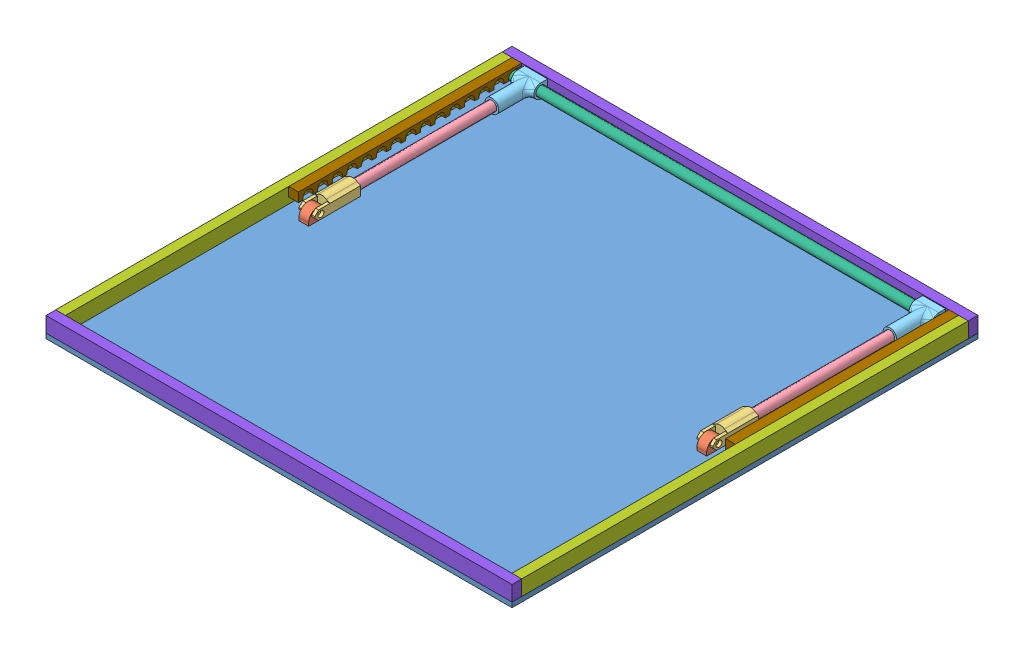
SolidWorks assembly second half tabletop v2, configuration Default. Lengths in mm.
Overall size (304.8 13.26 304.8).
17 component instances, 9 part files, 13 mates.
Components (placement in the parent):
- Tabletop-1: Tabletop [Default] at origin size (304.8 3.17 304.8)
- Leg_AttatchV2-1: Leg_AttatchV2 [Default] at (-133.35 5.175 6) x (0 0 -1) z (1 0 0) size (12 8 6.35)
- Leg_AttatchV2-2: Leg_AttatchV2 [Default] at (127 5.175 6) x (0 0 -1) z (1 0 0) size (12 8 6.35)
- Leg_Adapter-1: Leg_Adapter [Default] at (-130.175 8.1975 -26) x (1 0 0) z (0 -0.000865 1) size (10.35 10 30)
- Leg_Adapter-2: Leg_Adapter [Default] at (130.175 8.1975 -26) x (1 0 0) z (0 -0.000865 1) size (10.35 10 30)
- Leg_v2-1: Leg_v2 [Default] at (130.175 8.2935 -136.9999) x (0.583854 -0.811858 -0.000702) z (0 -0.000865 1) size (6.35 6.35 126)
- Leg_v2-2: Leg_v2 [Default] at (-130.175 8.1845 -11) x (-0.583854 -0.811858 -0.000702) z (0 0.000865 -1) size (6.35 6.35 126)
- Crossbar Adaptor-1: Crossbar Adaptor [Default] at (122.675 8.2974 -141.4999) x (0 1 0.000865) z (1 0 0) size (9 29 15)
- Crossbar Adaptor-2: Crossbar Adaptor [Default] at (-137.675 8.2974 -141.4999) x (0 1 0.000865) z (1 0 0) size (9 29 15)
- Crossbar_v2-1: Crossbar_v2 [Default] at (146.05 8.2974 -141.4999) x (0 -0.987363 0.158473) z (-1 0 0) size (6.35 6.35 292.1)
- Frame_Subassm-1: Frame_Subassm [Default] at (146.05 8.2172 0.0014) x (0 -0.000277 1) z (1 0 0) size (304.8 10 304.8)
  - DepthFrame-1: DepthFrame [Default] at origin size (292.1 10 6.35)
  - WidthFrame-2: WidthFrame [Default] at (146.05 0 -146.05) x (0 0 1) z (0 1 0) size (304.8 6.35 10)
  - DepthFrame-2: DepthFrame [Default] at (0 0 -298.45) size (292.1 10 6.35)
  - WidthFrame-3: WidthFrame [Default] at (-146.05 0 -146.05) x (0 0 1) z (0 -1 0) size (304.8 6.35 10)
  - Slots-1: Slots [Default] at (-146.05 -5 -6.35) size (146.05 6 6.35)
  - Slots-2: Slots [Default] at (-146.05 -5 -292.1) size (146.05 6 6.35)
Mates (geometry in assembly coordinates):
- Coincident1: coincident anti-aligned: plane of Tabletop-1 through (0 3.175 0) normal (0 1 0); plane of Leg_AttatchV2-1 through (-133.35 3.175 6) normal (0 -1 0)
- Coincident2: coincident anti-aligned: line of Tabletop-1 through (-127 3.175 0) axis (0 0 -1); line of Leg_AttatchV2-1 through (-127 3.175 -6) axis (0 0 1)
- Coincident3: coincident aligned: line of Tabletop-1 through (-138.2527 3.175 -6) axis (1 0 0); line of Leg_AttatchV2-1 through (-133.35 3.175 -6) axis (1 0 0)
- Concentric1: concentric aligned: cylinder of Leg_AttatchV2-1 through (-127 8.175 0) axis (-1 0 0) radius 2; cylinder of Leg_Adapter-1 through (-125 8.175 0) axis (-1 0 0) radius 2
- Width1: width anti-aligned: plane of Leg_Adapter-1 through (-133.35 5.203 -32.3271) normal (1 0 0); plane of Leg_AttatchV2-1 through (-127 5.203 -32.3271) normal (-1 0 0); plane of Leg_Adapter-1 through (-133.35 5.175 0) normal (-1 0 0); plane of Leg_AttatchV2-1 through (-127 5.175 0) normal (1 0 0)
- Concentric2: concentric aligned: cylinder of Leg_Adapter-2 through (130.175 8.1845 -11) axis (0 0.000865 -1) radius 3; cylinder of Leg_v2-1 through (130.175 8.1845 -11) axis (0 0.000865 -1) radius 3.175
- Coincident4: coincident anti-aligned: plane of Leg_Adapter-2 through (130.175 8.1845 -11) normal (0 0.000865 -1); plane of Leg_v2-1 through (130.175 8.1845 -11) normal (0 -0.000865 1)
- Concentric3: concentric aligned: cylinder of Leg_v2-1 through (130.175 8.1845 -11) axis (0 0.000865 -1) radius 3.175; cylinder of Crossbar Adaptor-1 through (130.175 8.2762 -117) axis (0 0.000865 -1) radius 2.5
- Coincident5: coincident anti-aligned: plane of Leg_v2-1 through (130.175 8.2935 -136.9999) normal (0 0.000865 -1); plane of Crossbar Adaptor-1 through (130.175 8.2935 -136.9999) normal (0 -0.000865 1)
- Concentric8: concentric anti-aligned: cylinder of Crossbar Adaptor-1 through (137.675 8.2974 -141.4999) axis (-1 0 0) radius 2.5; cylinder of Crossbar_v2-1 through (-146.05 8.2974 -141.4999) axis (1 0 0) radius 3.175
- Width2: width anti-aligned: plane of Tabletop-1 through (152.4 3.175 -152.4) normal (1 0 0); plane of Crossbar_v2-1 through (-152.4 3.175 -152.4) normal (-1 0 0); plane of Tabletop-1 through (-146.05 8.2974 -141.4999) normal (-1 0 0); plane of Crossbar_v2-1 through (146.05 8.2974 -141.4999) normal (1 0 0)
- Coincident6: coincident aligned: line of Tabletop-1 through (-152.4 3.175 152.4) axis (1 0 0); line of Frame_Subassm-1/WidthFrame-2 through (-152.4 3.175 152.4) axis (1 0 0)
- Width3: width anti-aligned: plane of Frame_Subassm-1/DepthFrame-2 through (-152.4 8.2172 0.0014) normal (-1 0 0); plane of Tabletop-1 through (152.4 8.2172 0.0014) normal (1 0 0); plane of Frame_Subassm-1/DepthFrame-1 through (152.4 3.175 -152.4) normal (1 0 0); plane of Tabletop-1 through (-152.4 3.175 -152.4) normal (-1 0 0)
